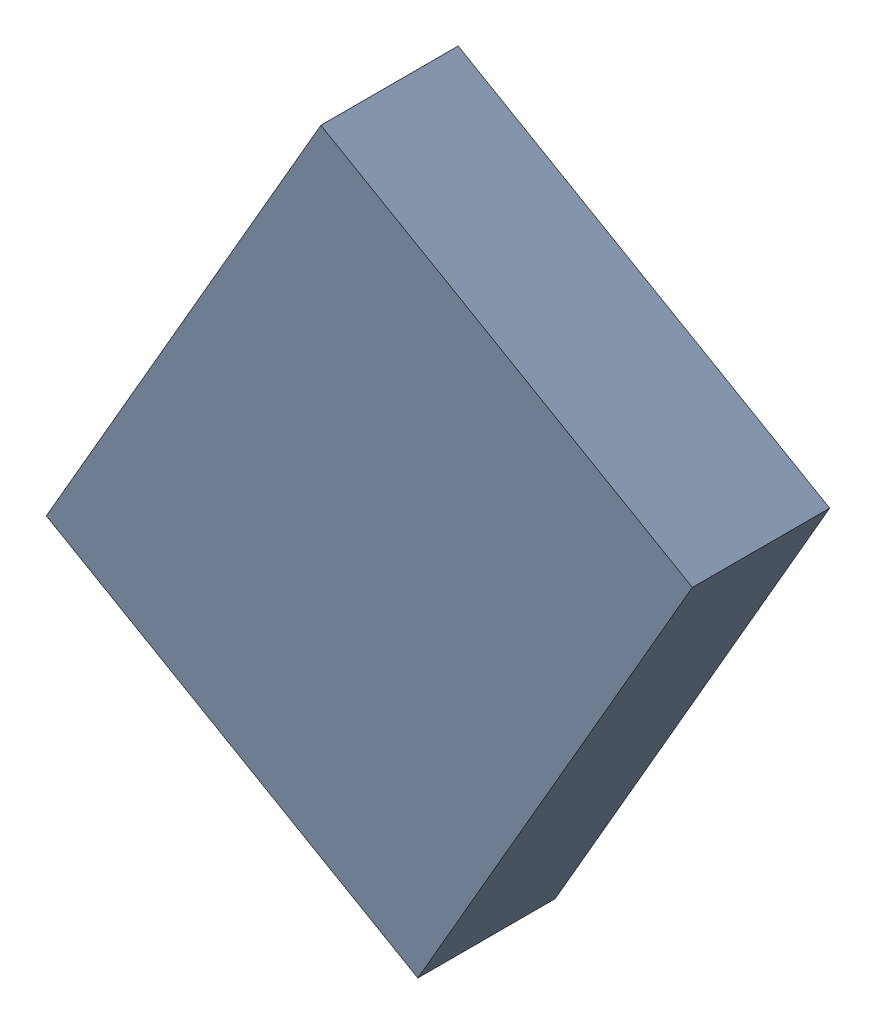
SolidWorks assembly X_TDA_1_TDA3, configuration Standard. Lengths in mm.
Overall size (3.77 4.02 0.8).
2 component instances, 1 part files, 0 mates.
Components (placement in the parent):
- 668293800-1: 668293800 [Standard] at (35.1741 -22.7679 0) size (3.77 4.02 0.8)
  - Extruded-1: Extruded [Standard] at origin size (3.77 4.02 0.8)
